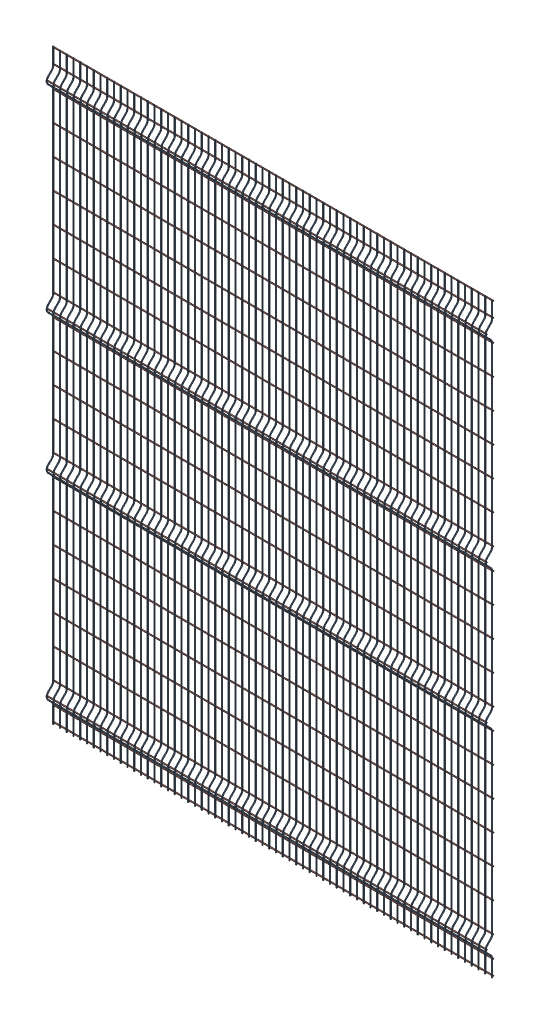
SolidWorks assembly Painel Lync Pro 1500 x 2000 step, configuration Valor predeterminado. Lengths in mm.
Overall size (1500 2000 28).
116 component instances, 2 part files, 0 mates.
Components (placement in the parent):
- Painel Lync Pro 1500 x 2000 step.STEP-1: Painel Lync Pro 1500 x 2000 step.STEP [Valor predeterminado] at origin size (1500 2000 28)
  - Arame vertical.STEP-1: Arame vertical.STEP [Valor predeterminado] at (-259.8823 -1220.0686 1996) size (3 2000 25)
  - Arame vertical.STEP-2: Arame vertical.STEP [Valor predeterminado] at (-282.8823 -1220.0686 1996) size (3 2000 25)
  - Arame vertical.STEP-3: Arame vertical.STEP [Valor predeterminado] at (-305.8823 -1220.0686 1996) size (3 2000 25)
  - Arame vertical.STEP-4: Arame vertical.STEP [Valor predeterminado] at (-328.8823 -1220.0686 1996) size (3 2000 25)
  - Arame vertical.STEP-5: Arame vertical.STEP [Valor predeterminado] at (-351.8823 -1220.0686 1996) size (3 2000 25)
  - Arame vertical.STEP-6: Arame vertical.STEP [Valor predeterminado] at (-374.8823 -1220.0686 1996) size (3 2000 25)
  - Arame vertical.STEP-7: Arame vertical.STEP [Valor predeterminado] at (-397.8823 -1220.0686 1996) size (3 2000 25)
  - Arame vertical.STEP-8: Arame vertical.STEP [Valor predeterminado] at (-420.8823 -1220.0686 1996) size (3 2000 25)
  - Arame vertical.STEP-9: Arame vertical.STEP [Valor predeterminado] at (-443.8823 -1220.0686 1996) size (3 2000 25)
  - Arame vertical.STEP-10: Arame vertical.STEP [Valor predeterminado] at (-466.8823 -1220.0686 1996) size (3 2000 25)
  - Arame vertical.STEP-11: Arame vertical.STEP [Valor predeterminado] at (-489.8823 -1220.0686 1996) size (3 2000 25)
  - Arame vertical.STEP-12: Arame vertical.STEP [Valor predeterminado] at (-512.8823 -1220.0686 1996) size (3 2000 25)
  - Arame vertical.STEP-13: Arame vertical.STEP [Valor predeterminado] at (-535.8823 -1220.0686 1996) size (3 2000 25)
  - Arame vertical.STEP-14: Arame vertical.STEP [Valor predeterminado] at (-558.8823 -1220.0686 1996) size (3 2000 25)
  - Arame vertical.STEP-15: Arame vertical.STEP [Valor predeterminado] at (-581.8823 -1220.0686 1996) size (3 2000 25)
  - Arame vertical.STEP-16: Arame vertical.STEP [Valor predeterminado] at (-604.8823 -1220.0686 1996) size (3 2000 25)
  - Arame vertical.STEP-17: Arame vertical.STEP [Valor predeterminado] at (-627.8823 -1220.0686 1996) size (3 2000 25)
  - Arame vertical.STEP-18: Arame vertical.STEP [Valor predeterminado] at (-650.8823 -1220.0686 1996) size (3 2000 25)
  - Arame vertical.STEP-19: Arame vertical.STEP [Valor predeterminado] at (-673.8823 -1220.0686 1996) size (3 2000 25)
  - Arame vertical.STEP-20: Arame vertical.STEP [Valor predeterminado] at (-696.8823 -1220.0686 1996) size (3 2000 25)
  - Arame vertical.STEP-21: Arame vertical.STEP [Valor predeterminado] at (-719.8823 -1220.0686 1996) size (3 2000 25)
  - Arame vertical.STEP-22: Arame vertical.STEP [Valor predeterminado] at (-742.8823 -1220.0686 1996) size (3 2000 25)
  - Arame vertical.STEP-23: Arame vertical.STEP [Valor predeterminado] at (-765.8823 -1220.0686 1996) size (3 2000 25)
  - Arame vertical.STEP-24: Arame vertical.STEP [Valor predeterminado] at (-788.8823 -1220.0686 1996) size (3 2000 25)
  - Arame vertical.STEP-25: Arame vertical.STEP [Valor predeterminado] at (-811.8823 -1220.0686 1996) size (3 2000 25)
  - Arame vertical.STEP-26: Arame vertical.STEP [Valor predeterminado] at (-834.8823 -1220.0686 1996) size (3 2000 25)
  - Arame vertical.STEP-27: Arame vertical.STEP [Valor predeterminado] at (-857.8823 -1220.0686 1996) size (3 2000 25)
  - Arame vertical.STEP-28: Arame vertical.STEP [Valor predeterminado] at (-880.8823 -1220.0686 1996) size (3 2000 25)
  - Arame vertical.STEP-29: Arame vertical.STEP [Valor predeterminado] at (-903.8823 -1220.0686 1996) size (3 2000 25)
  - Arame vertical.STEP-30: Arame vertical.STEP [Valor predeterminado] at (-926.8823 -1220.0686 1996) size (3 2000 25)
  - Arame vertical.STEP-31: Arame vertical.STEP [Valor predeterminado] at (-949.8823 -1220.0686 1996) size (3 2000 25)
  - Arame vertical.STEP-32: Arame vertical.STEP [Valor predeterminado] at (-972.8823 -1220.0686 1996) size (3 2000 25)
  - Arame vertical.STEP-33: Arame vertical.STEP [Valor predeterminado] at (-995.8823 -1220.0686 1996) size (3 2000 25)
  - Arame vertical.STEP-34: Arame vertical.STEP [Valor predeterminado] at (-1018.8823 -1220.0686 1996) size (3 2000 25)
  - Arame vertical.STEP-35: Arame vertical.STEP [Valor predeterminado] at (-1041.8823 -1220.0686 1996) size (3 2000 25)
  - Arame vertical.STEP-36: Arame vertical.STEP [Valor predeterminado] at (-1064.8823 -1220.0686 1996) size (3 2000 25)
  - Arame vertical.STEP-37: Arame vertical.STEP [Valor predeterminado] at (-1087.8823 -1220.0686 1996) size (3 2000 25)
  - Arame vertical.STEP-38: Arame vertical.STEP [Valor predeterminado] at (-1110.8823 -1220.0686 1996) size (3 2000 25)
  - Arame vertical.STEP-39: Arame vertical.STEP [Valor predeterminado] at (-1133.8823 -1220.0686 1996) size (3 2000 25)
  - Arame vertical.STEP-40: Arame vertical.STEP [Valor predeterminado] at (-1156.8823 -1220.0686 1996) size (3 2000 25)
  - Arame vertical.STEP-41: Arame vertical.STEP [Valor predeterminado] at (-1179.8823 -1220.0686 1996) size (3 2000 25)
  - Arame vertical.STEP-42: Arame vertical.STEP [Valor predeterminado] at (-1202.8823 -1220.0686 1996) size (3 2000 25)
  - Arame vertical.STEP-43: Arame vertical.STEP [Valor predeterminado] at (-1225.8823 -1220.0686 1996) size (3 2000 25)
  - Arame vertical.STEP-44: Arame vertical.STEP [Valor predeterminado] at (-1248.8823 -1220.0686 1996) size (3 2000 25)
  - Arame vertical.STEP-45: Arame vertical.STEP [Valor predeterminado] at (-1271.8823 -1220.0686 1996) size (3 2000 25)
  - Arame vertical.STEP-46: Arame vertical.STEP [Valor predeterminado] at (-1294.8823 -1220.0686 1996) size (3 2000 25)
  - Arame vertical.STEP-47: Arame vertical.STEP [Valor predeterminado] at (-1317.8823 -1220.0686 1996) size (3 2000 25)
  - Arame vertical.STEP-48: Arame vertical.STEP [Valor predeterminado] at (-1340.8823 -1220.0686 1996) size (3 2000 25)
  - Arame vertical.STEP-49: Arame vertical.STEP [Valor predeterminado] at (-1363.8823 -1220.0686 1996) size (3 2000 25)
  - Arame vertical.STEP-50: Arame vertical.STEP [Valor predeterminado] at (-1386.8823 -1220.0686 1996) size (3 2000 25)
  - Arame vertical.STEP-51: Arame vertical.STEP [Valor predeterminado] at (-1409.8823 -1220.0686 1996) size (3 2000 25)
  - Arame vertical.STEP-52: Arame vertical.STEP [Valor predeterminado] at (-1432.8823 -1220.0686 1996) size (3 2000 25)
  - Arame vertical.STEP-53: Arame vertical.STEP [Valor predeterminado] at (-1455.8823 -1220.0686 1996) size (3 2000 25)
  - Arame vertical.STEP-54: Arame vertical.STEP [Valor predeterminado] at (-1478.8823 -1220.0686 1996) size (3 2000 25)
  - Arame vertical.STEP-55: Arame vertical.STEP [Valor predeterminado] at (-1501.8823 -1220.0686 1996) size (3 2000 25)
  - Arame vertical.STEP-56: Arame vertical.STEP [Valor predeterminado] at (-1524.8823 -1220.0686 1996) size (3 2000 25)
  - Arame vertical.STEP-57: Arame vertical.STEP [Valor predeterminado] at (-1547.8823 -1220.0686 1996) size (3 2000 25)
  - Arame vertical.STEP-58: Arame vertical.STEP [Valor predeterminado] at (-1570.8823 -1220.0686 1996) size (3 2000 25)
  - Arame vertical.STEP-59: Arame vertical.STEP [Valor predeterminado] at (-1593.8823 -1220.0686 1996) size (3 2000 25)
  - Arame vertical.STEP-60: Arame vertical.STEP [Valor predeterminado] at (-1616.8823 -1220.0686 1996) size (3 2000 25)
  - Arame vertical.STEP-61: Arame vertical.STEP [Valor predeterminado] at (-1639.8823 -1220.0686 1996) size (3 2000 25)
  - Arame vertical.STEP-62: Arame vertical.STEP [Valor predeterminado] at (-1662.8823 -1220.0686 1996) size (3 2000 25)
  - Arame vertical.STEP-63: Arame vertical.STEP [Valor predeterminado] at (-1685.8823 -1220.0686 1996) size (3 2000 25)
  - Arame vertical.STEP-64: Arame vertical.STEP [Valor predeterminado] at (-1708.8823 -1220.0686 1996) size (3 2000 25)
  - Arame vertical.STEP-65: Arame vertical.STEP [Valor predeterminado] at (-1731.8823 -1220.0686 1996) size (3 2000 25)
  - Arame horizontal.STEP-1: Arame horizontal.STEP [Valor predeterminado] at (-258.3823 -1128.0686 2015) size (1500 3 3)
  - Arame vertical.STEP-66: Arame vertical.STEP [Valor predeterminado] at (-1754.8823 -1220.0686 1996) size (3 2000 25)
  - Arame horizontal.STEP-2: Arame horizontal.STEP [Valor predeterminado] at (-258.3823 -458.0686 2015) size (1500 3 3)
  - Arame horizontal.STEP-3: Arame horizontal.STEP [Valor predeterminado] at (-258.3823 14.9314 2015) size (1500 3 3)
  - Arame horizontal.STEP-4: Arame horizontal.STEP [Valor predeterminado] at (-258.3823 687.9314 2015) size (1500 3 3)
  - Arame horizontal.STEP-5: Arame horizontal.STEP [Valor predeterminado] at (-258.3823 -1165.5686 1993) size (1500 3 3)
  - Arame horizontal.STEP-6: Arame horizontal.STEP [Valor predeterminado] at (-258.3823 -1215.5686 1993) size (1500 3 3)
  - Arame horizontal.STEP-7: Arame horizontal.STEP [Valor predeterminado] at (-258.3823 775.4314 1993) size (1500 3 3)
  - Arame horizontal.STEP-8: Arame horizontal.STEP [Valor predeterminado] at (-258.3823 725.4314 1993) size (1500 3 3)
  - Arame horizontal.STEP-9: Arame horizontal.STEP [Valor predeterminado] at (-258.3823 -793.0686 1993) size (1500 3 3)
  - Arame horizontal.STEP-10: Arame horizontal.STEP [Valor predeterminado] at (-258.3823 -693.0686 1993) size (1500 3 3)
  - Arame horizontal.STEP-11: Arame horizontal.STEP [Valor predeterminado] at (-258.3823 -593.0686 1993) size (1500 3 3)
  - Arame horizontal.STEP-12: Arame horizontal.STEP [Valor predeterminado] at (-258.3823 -493.0686 1993) size (1500 3 3)
  - Arame horizontal.STEP-13: Arame horizontal.STEP [Valor predeterminado] at (-258.3823 -893.0686 1993) size (1500 3 3)
  - Arame horizontal.STEP-14: Arame horizontal.STEP [Valor predeterminado] at (-258.3823 -993.0686 1993) size (1500 3 3)
  - Arame horizontal.STEP-15: Arame horizontal.STEP [Valor predeterminado] at (-258.3823 -1093.0686 1993) size (1500 3 3)
  - Arame horizontal.STEP-16: Arame horizontal.STEP [Valor predeterminado] at (-258.3823 -793.0686 1993) size (1500 3 3)
  - Arame horizontal.STEP-17: Arame horizontal.STEP [Valor predeterminado] at (-258.3823 -893.0686 1993) size (1500 3 3)
  - Arame horizontal.STEP-18: Arame horizontal.STEP [Valor predeterminado] at (-258.3823 -993.0686 1993) size (1500 3 3)
  - Arame horizontal.STEP-19: Arame horizontal.STEP [Valor predeterminado] at (-258.3823 -693.0686 1993) size (1500 3 3)
  - Arame horizontal.STEP-20: Arame horizontal.STEP [Valor predeterminado] at (-258.3823 -793.0686 1993) size (1500 3 3)
  - Arame horizontal.STEP-21: Arame horizontal.STEP [Valor predeterminado] at (-258.3823 -893.0686 1993) size (1500 3 3)
  - Arame horizontal.STEP-22: Arame horizontal.STEP [Valor predeterminado] at (-258.3823 -593.0686 1993) size (1500 3 3)
  - Arame horizontal.STEP-23: Arame horizontal.STEP [Valor predeterminado] at (-258.3823 -693.0686 1993) size (1500 3 3)
  - Arame horizontal.STEP-24: Arame horizontal.STEP [Valor predeterminado] at (-258.3823 -793.0686 1993) size (1500 3 3)
  - Arame horizontal.STEP-25: Arame horizontal.STEP [Valor predeterminado] at (-258.3823 351.4314 1993) size (1500 3 3)
  - Arame horizontal.STEP-26: Arame horizontal.STEP [Valor predeterminado] at (-258.3823 251.4314 1993) size (1500 3 3)
  - Arame horizontal.STEP-27: Arame horizontal.STEP [Valor predeterminado] at (-258.3823 151.4314 1993) size (1500 3 3)
  - Arame horizontal.STEP-28: Arame horizontal.STEP [Valor predeterminado] at (-258.3823 51.4314 1993) size (1500 3 3)
  - Arame horizontal.STEP-29: Arame horizontal.STEP [Valor predeterminado] at (-258.3823 451.4314 1993) size (1500 3 3)
  - Arame horizontal.STEP-30: Arame horizontal.STEP [Valor predeterminado] at (-258.3823 351.4314 1993) size (1500 3 3)
  - Arame horizontal.STEP-31: Arame horizontal.STEP [Valor predeterminado] at (-258.3823 251.4314 1993) size (1500 3 3)
  - Arame horizontal.STEP-32: Arame horizontal.STEP [Valor predeterminado] at (-258.3823 151.4314 1993) size (1500 3 3)
  - Arame horizontal.STEP-33: Arame horizontal.STEP [Valor predeterminado] at (-258.3823 551.4314 1993) size (1500 3 3)
  - Arame horizontal.STEP-34: Arame horizontal.STEP [Valor predeterminado] at (-258.3823 451.4314 1993) size (1500 3 3)
  - Arame horizontal.STEP-35: Arame horizontal.STEP [Valor predeterminado] at (-258.3823 351.4314 1993) size (1500 3 3)
  - Arame horizontal.STEP-36: Arame horizontal.STEP [Valor predeterminado] at (-258.3823 251.4314 1993) size (1500 3 3)
  - Arame horizontal.STEP-37: Arame horizontal.STEP [Valor predeterminado] at (-258.3823 651.4314 1993) size (1500 3 3)
  - Arame horizontal.STEP-38: Arame horizontal.STEP [Valor predeterminado] at (-258.3823 551.4314 1993) size (1500 3 3)
  - Arame horizontal.STEP-39: Arame horizontal.STEP [Valor predeterminado] at (-258.3823 451.4314 1993) size (1500 3 3)
  - Arame horizontal.STEP-40: Arame horizontal.STEP [Valor predeterminado] at (-258.3823 351.4314 1993) size (1500 3 3)
  - Arame horizontal.STEP-41: Arame horizontal.STEP [Valor predeterminado] at (-258.3823 -221.5686 1993) size (1500 3 3)
  - Arame horizontal.STEP-42: Arame horizontal.STEP [Valor predeterminado] at (-258.3823 -321.5686 1993) size (1500 3 3)
  - Arame horizontal.STEP-43: Arame horizontal.STEP [Valor predeterminado] at (-258.3823 -421.5686 1993) size (1500 3 3)
  - Arame horizontal.STEP-44: Arame horizontal.STEP [Valor predeterminado] at (-258.3823 -121.5686 1993) size (1500 3 3)
  - Arame horizontal.STEP-45: Arame horizontal.STEP [Valor predeterminado] at (-258.3823 -221.5686 1993) size (1500 3 3)
  - Arame horizontal.STEP-46: Arame horizontal.STEP [Valor predeterminado] at (-258.3823 -321.5686 1993) size (1500 3 3)
  - Arame horizontal.STEP-47: Arame horizontal.STEP [Valor predeterminado] at (-258.3823 -21.5686 1993) size (1500 3 3)
  - Arame horizontal.STEP-48: Arame horizontal.STEP [Valor predeterminado] at (-258.3823 -121.5686 1993) size (1500 3 3)
  - Arame horizontal.STEP-49: Arame horizontal.STEP [Valor predeterminado] at (-258.3823 -221.5686 1993) size (1500 3 3)
